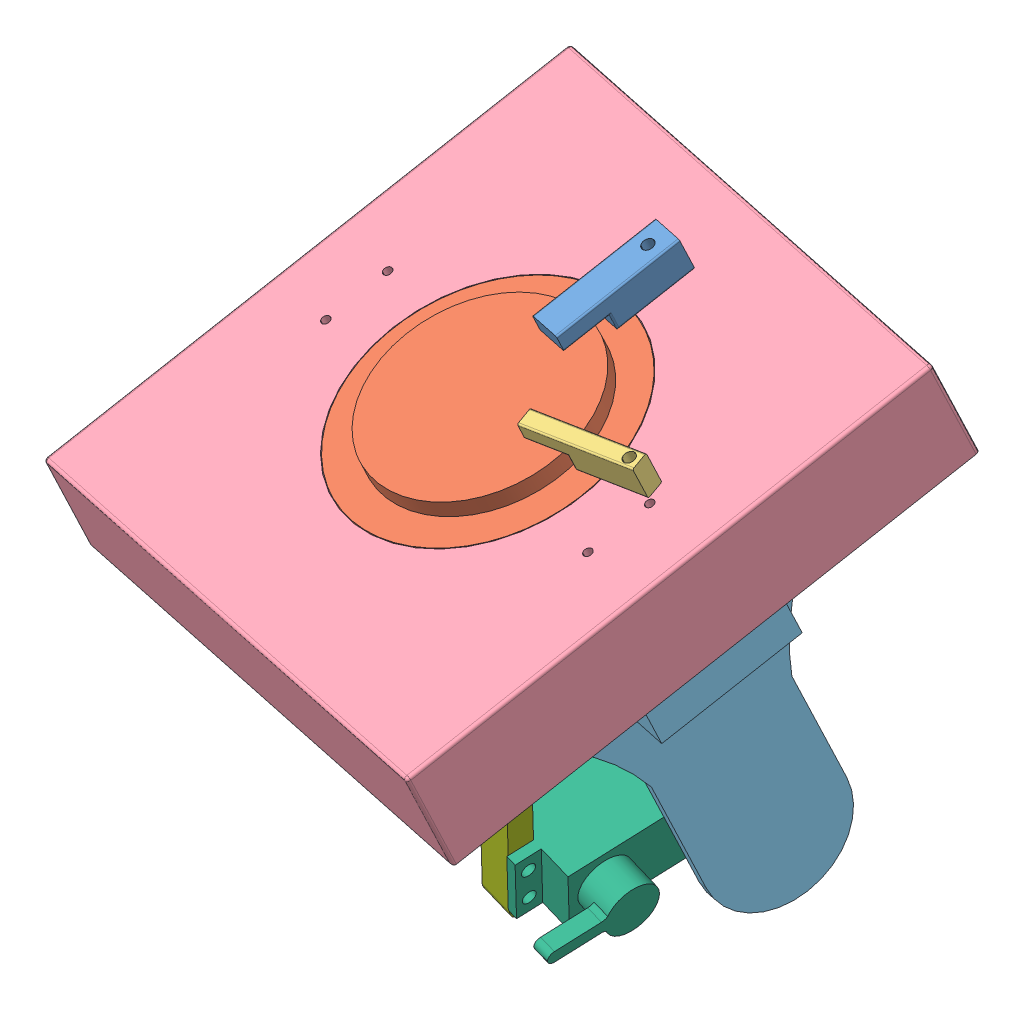
SolidWorks assembly Shaker_v2, configuration Default. Lengths in mm.
Overall size (187.51 177.9 208.59).
8 component instances, 7 part files, 23 mates.
Components (placement in the parent):
- Clamp_Shaker_v2-1: Clamp_Shaker_v2 [Default] at (-418.1837 112.7909 -255.8392) x (-0.196085 -0.396215 0.896975) z (-0.106456 0.917928 0.382198) size (35 10 10)
- Outline for Chamber-1: Outline for Chamber [Default] at (-425.7167 97.733 -221.7728) x (-0.881334 0.09085 -0.463678) z (-0.460346 -0.386205 0.799329) size (78 15 78)
- Small_Clamp-2: Small_Clamp [Default] at (-390.6112 105.8162 -218.326) x (0.99089 0.129825 -0.035804) z (0.106456 -0.917928 -0.382198) size (35 5 10)
- Platform_Shaker_COPYNEW-1: Platform_Shaker_COPYNEW [Default] at (-425.1844 93.1434 -223.6838) x (-0.974791 -0.020545 -0.222171) z (-0.106456 0.917928 0.382198) size (150 150 30)
- Bracket for Platform-3: Bracket for Platform [Default] at (-363.354 6.1813 -270.8776) x (-0.196085 -0.396215 0.896975) z (-0.974791 -0.020545 -0.222171) size (130 100 30)
- Bracket for Platform-6: Bracket for Platform [Default] at (-464.7774 -11.6396 -256.327) x (0.196085 0.396215 -0.896975) z (0.974791 0.020545 0.222171) size (130 100 30)
- Servomotor CAD-1: Servomotor CAD [Default] at (-419.4589 -8.0903 -235.2559) x (-0.159616 -0.204493 0.965767) z (0.963778 -0.244028 0.107616) size (60.71 20 50.4)
- Servo Mount-3: Servo Mount [Default] at (-403.9779 -11.4043 -265.8183) x (0.159616 0.204493 -0.965767) z (-0.963778 0.244028 -0.107616) size (54 38.64 37.7)
Mates (geometry in assembly coordinates):
- Concentric6: concentric aligned: cylinder of Outline for Chamber-1 through (-424.1198 83.9641 -227.5058) axis (-0.106456 0.917928 0.382198) radius 39; cylinder of Platform_Shaker_COPYNEW-1 through (-424.1198 83.9641 -227.5058) axis (-0.106456 0.917928 0.382198) radius 39.25
- Coincident41: coincident anti-aligned: plane of Platform_Shaker_COPYNEW-1 through (-421.9907 65.6055 -235.1498) normal (0.106456 -0.917928 -0.382198); plane of Bracket for Platform-5 through (-531.5759 -78.4007 -54.786) normal (0 0.990565 -0.13704)
- Coincident42: coincident aligned: line of Platform_Shaker_COPYNEW-1 through (-508.6356 34.7653 -185.2143) axis (0.196085 0.396215 -0.896975); line of Bracket for Platform-5 through (-531.5759 -66.7522 29.4121) axis (0 -0.13704 -0.990565)
- ProfileCenter1: profile center aligned: circle of Servo Mount-2; circle of Servomotor CAD-1
- Concentric9: concentric anti-aligned: circle of Servo Mount-2; circle of Servomotor CAD-1
- Concentric11: concentric aligned: circle of Servo Mount-1; circle of Servomotor CAD-1
- Concentric13: concentric aligned: circle of Servo Mount-1; cylinder of Servomotor CAD-1 through (-417.315 -27.568 -222.5202) axis (0.963778 -0.244028 0.107616) radius 1.9389
- Coincident54: coincident anti-aligned: plane of Servo Mount-1 through (-317.2496 -254.9359 -35.8114) normal (0.965109 0.019885 0.261092); plane of Servomotor CAD-1 through (-414.8659 -34.0863 -219.7421) normal (-0.963778 0.244028 -0.107616)
- Coincident55: coincident anti-aligned: plane of Platform_Shaker_COPYNEW-1 through (-421.9907 65.6055 -235.1498) normal (0.106456 -0.917928 -0.382198); plane of Bracket for Platform-6 through (-469.778 56.7567 -227.208) normal (-0.106456 0.917928 0.382198)
- Coincident56: coincident aligned: plane of Platform_Shaker_COPYNEW-1 through (-480.3937 93.7808 -319.0857) normal (-0.974791 -0.020545 -0.222171); plane of Bracket for Platform-6 through (-491.0967 -12.1943 -262.3256) normal (-0.974791 -0.020545 -0.222171)
- Coincident57: coincident anti-aligned: plane of Platform_Shaker_COPYNEW-1 through (-421.9907 65.6055 -235.1498) normal (0.106456 -0.917928 -0.382198); plane of Bracket for Platform-3 through (-374.2034 74.4543 -243.0916) normal (-0.106456 0.917928 0.382198)
- Coincident58: coincident aligned: plane of Platform_Shaker_COPYNEW-1 through (-334.175 96.8625 -285.7601) normal (0.974791 0.020545 0.222171); plane of Bracket for Platform-3 through (-337.0346 6.736 -264.8789) normal (0.974791 0.020545 0.222171)
- Coincident62: coincident: point of Platform_Shaker_COPYNEW-1; point of Bracket for Platform-3
- Coincident63: coincident: point of Platform_Shaker_COPYNEW-1; point of Bracket for Platform-6
- Concentric15: concentric aligned: cylinder of Servomotor CAD-1 through (-409.7731 -17.9057 -268.1527) axis (0.963778 -0.244028 0.107616) radius 1.9389; cylinder of Servo Mount-3 through (-424.9526 -14.0623 -269.8476) axis (0.963778 -0.244028 0.107616) radius 2.05
- Coincident64: coincident anti-aligned: plane of Servomotor CAD-1 through (-406.1668 -22.9414 -272.3764) normal (-0.963778 0.244028 -0.107616); plane of Servo Mount-3 through (-407.0338 -24.9624 -269.1941) normal (0.963778 -0.244028 0.107616)
- Parallel5: parallel aligned: plane of Servomotor CAD-1 through (-419.4589 -8.0903 -235.2559) normal (0.213668 0.947962 0.236037); plane of Servo Mount-3 through (-409.7519 9.9409 -258.6288) normal (0.213668 0.947962 0.236037)
- Coincident66: coincident anti-aligned: plane of Outline for Chamber-1 through (-424.1198 83.9641 -227.5058) normal (0.106456 -0.917928 -0.382198); plane of Platform_Shaker_COPYNEW-1 through (-424.1198 83.9641 -227.5058) normal (-0.106456 0.917928 0.382198)
- Concentric17: concentric aligned: cylinder of Small_Clamp-2 through (-376.3272 107.6877 -218.8422) axis (-0.106456 0.917928 0.382198) radius 1.7; circle of Platform_Shaker_COPYNEW-1
- Coincident68: coincident anti-aligned: plane of Small_Clamp-2 through (-389.5467 96.6369 -222.148) normal (0.106456 -0.917928 -0.382198); plane of Platform_Shaker_COPYNEW-1 through (-425.1844 93.1434 -223.6838) normal (-0.106456 0.917928 0.382198)
- Coincident69: coincident anti-aligned: plane of Clamp_Shaker_v2-1 through (-418.1837 112.7909 -255.8392) normal (0.106456 -0.917928 -0.382198); plane of Outline for Chamber-1 through (-425.7167 97.733 -221.7728) normal (-0.106456 0.917928 0.382198)
- Concentric18: concentric aligned: circle of Clamp_Shaker_v2-1; circle of Platform_Shaker_COPYNEW-1
- Parallel6: parallel aligned: plane of Clamp_Shaker_v2-1 through (-420.1584 124.2115 -270.7362) normal (-0.974791 -0.020545 -0.222171); plane of Platform_Shaker_COPYNEW-1 through (-480.3937 93.7808 -319.0857) normal (-0.974791 -0.020545 -0.222171)
